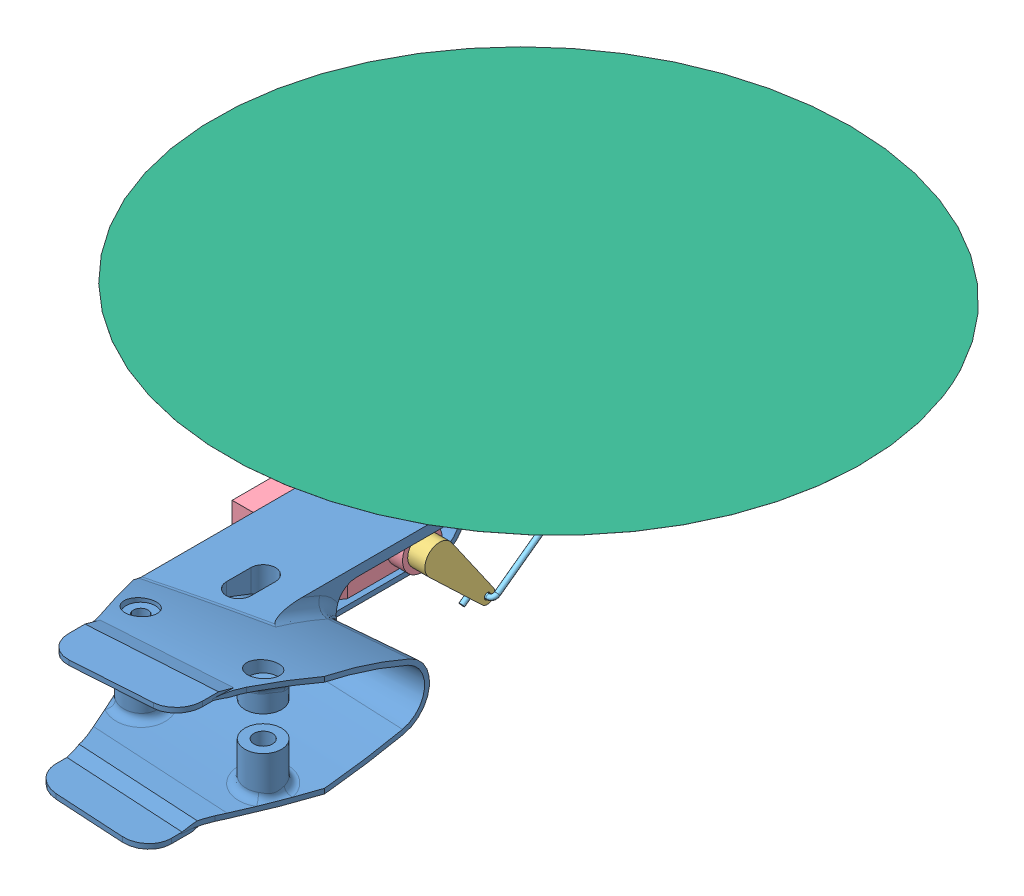
SolidWorks assembly Assem5, configuration Default. Lengths in mm.
Overall size (169 49.42 180.5).
6 component instances, 6 part files, 13 mates.
Components (placement in the parent):
- heewing6a-1: heewing6a [Default] at origin size (39 24.46 88.5)
- heewing5b-1: heewing5b [Default] at (-4.375 13.6413 -45.3449) x (-1 0 0) z (0 0.999236 -0.039087) size (20.37 21 14)
- horn-1: horn [Default] at (1.28 0.5 -20.2) x (0 -0.651073 0.759015) z (0 -0.759015 -0.651073) size (6 3.5 19.5)
- servo-1: servo [Default] at (-8.8 0.5 -15) x (0 0 -1) z (0 -1 0) size (27.5 26.33 8.5)
- link-1: link [Default] at (2.48 -3.2358 -40.4773) x (0 -0.808556 -0.58842) z (0 0.58842 -0.808556) size (1 9 29.5)
- motor-1: motor [Default] at (-4.375 15.6398 -45.4231) x (-0.425944 -0.035364 -0.904058) z (0.904749 -0.016649 -0.425619) size (127 16.51 127)
Mates (geometry in assembly coordinates):
- Concentric10: concentric anti-aligned: cylinder of horn-1 through (-2.22 0.5 -20.2) axis (1 0 0) radius 3; cylinder of servo-1 through (0.28 0.5 -20.2) axis (-1 0 0) radius 1.8
- Coincident2: coincident anti-aligned: plane of horn-1 through (-2.22 0.5 -20.2) normal (-1 0 0); plane of servo-1 through (-2.22 0.5 -20.2) normal (1 0 0)
- Concentric11: concentric aligned: cylinder of heewing5b-1 through (1.375 4.4137 -50.9885) axis (-1 0 0) radius 0.625; cylinder of link-1 through (1.48 4.4137 -50.9885) axis (-1 0 0) radius 0.5
- Concentric12: concentric aligned: cylinder of horn-1 through (0.18 -10.8852 -29.9661) axis (1 0 0) radius 0.625; cylinder of link-1 through (-0.52 -10.8852 -29.9661) axis (1 0 0) radius 0.5
- Concentric15: concentric aligned: cylinder of heewing5b-1 through (-4.375 15.6398 -45.4231) axis (0 -0.999236 0.039087) radius 2; cylinder of motor-1 through (-4.375 31.128 -46.0289) axis (0 -0.999236 0.039087) radius 10.65
- Coincident6: coincident anti-aligned: plane of heewing5b-1 through (-4.375 15.6398 -45.4231) normal (0 0.999236 -0.039087); plane of motor-1 through (-4.375 15.6398 -45.4231) normal (0 -0.999236 0.039087)
- Concentric16: concentric anti-aligned: cylinder of heewing5b-1 through (5.625 5 -36) axis (-1 0 0) radius 1; cylinder of heewing6a-1 through (-19.5 5 -36) axis (1 0 0) radius 0.9
- Distance1: distance = 0.7 mm: cylinder of link-1 through (2.48 -10.2968 -30.7746) axis (0 0.58842 -0.808556) radius 0.5; plane of horn-1 through (1.28 0.5 -20.2) normal (1 0 0)
- Coincident7: coincident anti-aligned: plane of heewing6a-1 through (-9.5 1 -4) normal (1 0 0); plane of servo-1 through (-9.5 0.5 -15) normal (-1 0 0)
- Concentric19: concentric aligned: cylinder of heewing6a-1 through (-19.5 0.5 -26.75) axis (1 0 0) radius 0.7; cylinder of servo-1 through (-9.5 0.5 -26.75) axis (1 0 0) radius 0.75
- Concentric20: concentric aligned: cylinder of heewing6a-1 through (-19.5 0.5 -3.25) axis (1 0 0) radius 0.7; cylinder of servo-1 through (-9.5 0.5 -3.25) axis (1 0 0) radius 0.75
- LimitAngle1: limit planar angle = 3.102495 rad anti-aligned: plane of heewing5b-1 through (-4.375 15.6398 -45.4231) normal (0 0.999236 -0.039087); plane of heewing6a-1 through (0.5 7 40.002) normal (0 1 0)
- Width1: width aligned: plane of heewing5b-1 through (-9.375 5 -36) normal (1 0 0); plane of heewing6a-1 through (0.625 5 -36) normal (-1 0 0); plane of heewing5b-1 through (0.5 7 40.002) normal (1 0 0); plane of heewing6a-1 through (-9.25 5 -36) normal (-1 0 0)
